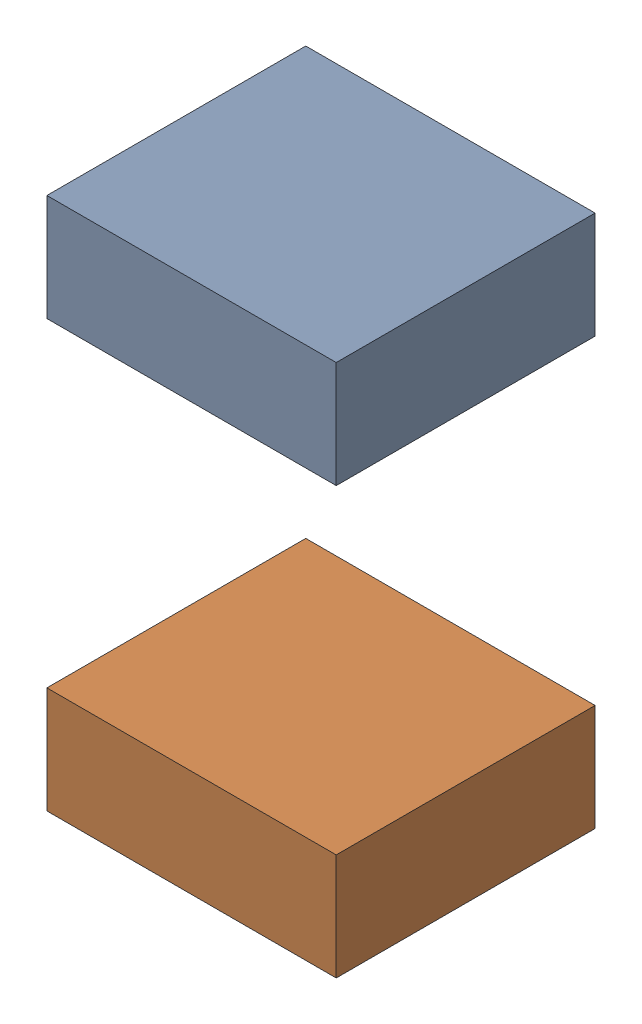
SolidWorks assembly C8, configuration 默认. Lengths in mm.
Overall size (0.95 1.75 0.85).
5 component instances, 1 part files, 0 mates.
Components (placement in the parent):
- 6241791616-1: 6241791616 [默认] at (39.37 19.304 -2.5414) (suppressed, hidden)
- 6241792176-1: 6241792176 [默认] at (39.37 20.004 -2.5414) size (0.95 0.35 0.85)
  - Extruded-1-1: Extruded-1 [默认] at origin size (0.95 0.35 0.85)
- 6241792176-2: 6241792176 [默认] at (39.37 18.604 -2.5414) size (0.95 0.35 0.85)
  - Extruded-1-1: Extruded-1 [默认] at origin size (0.95 0.35 0.85)
